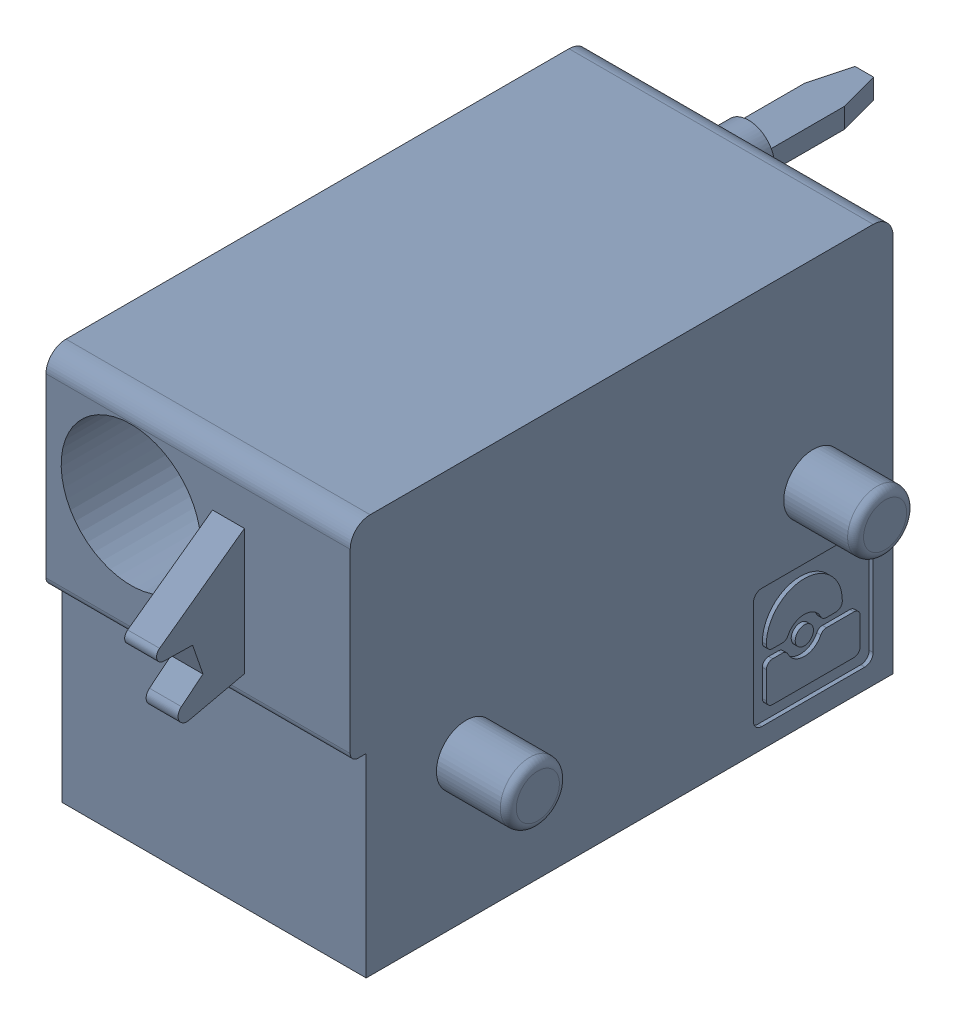
SolidWorks assembly J50, configuration Default. Lengths in mm.
Overall size (9.42 10 19.2).
2 component instances, 1 part files, 0 mates.
Components (placement in the parent):
- 1790377-1: 1790377 [Default] at (144.1451 -7.6199 0) x (0 1 0) z (1 0 0) size (10 19.2 9.42)
  - ffkdsa-v2-7.62-1: ffkdsa-v2-7.62 [Default] at (-23.7414 -38.158 -5.08) x (0 -1 0) z (0 0 1) size (19.2 10 9.42)
